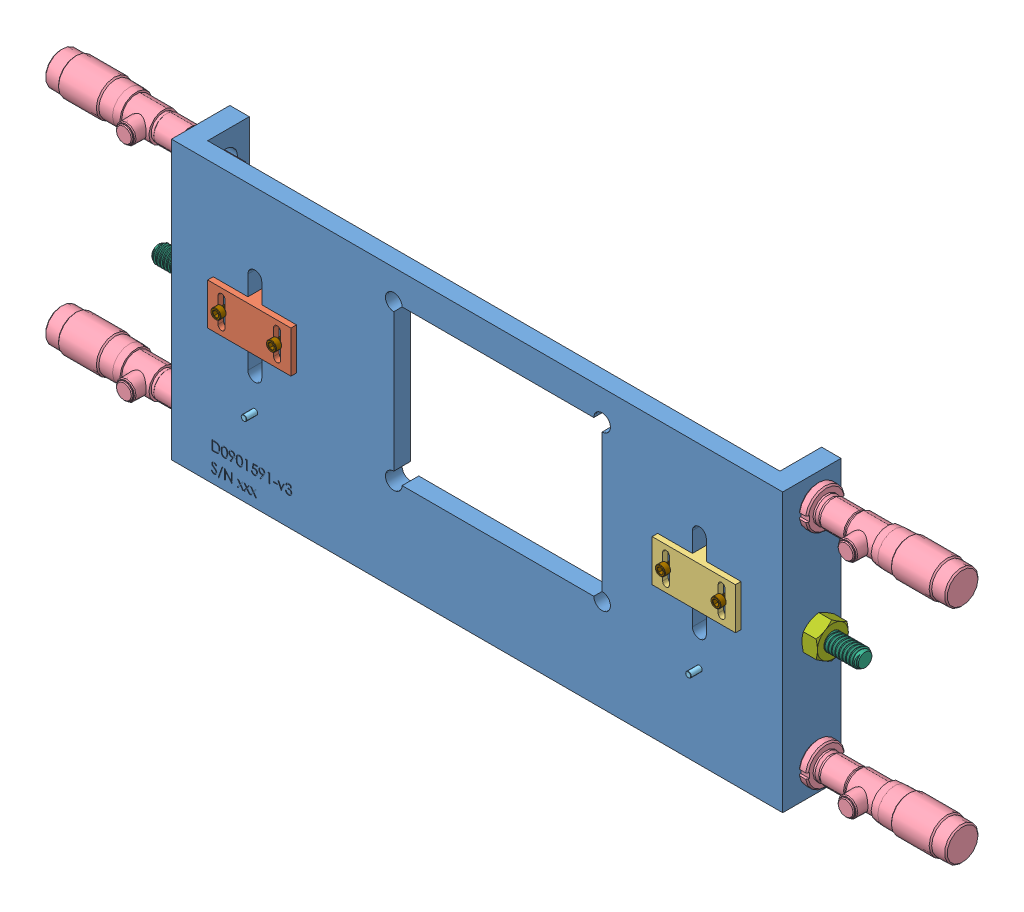
SolidWorks assembly Ear Bonding Jig Assembly, configuration Default. Lengths in mm.
Overall size (324.5 100 25.3).
20 component instances, 9 part files, 40 mates.
Components (placement in the parent):
- Baseplate-1: Baseplate [Default] at origin size (220 100 21)
- D1001633_T-piece-1: D1001633_T-piece [Default] at (0 -0.4 0) size (30 15 8)
- MVV_T_PIECE_1-1-1: MVV_T_PIECE_1-1 [Default] at (0 -0.4 0) size (30 15 8)
- Newport-HR-13-1: Newport-HR-13 [Default] at (-95.25 40 -6.5) x (0 1 0) z (0 0 1) size (14 67 16.68)
- Newport-HR-13-2: Newport-HR-13 [Default] at (-95.25 -40 -6.5) x (0 1 0) z (0 0 1) size (14 67 16.68)
- Newport-HR-13-3: Newport-HR-13 [Default] at (95.25 40 -6.5) x (0 -1 0) z (0 0 1) size (14 67 16.68)
- Newport-HR-13-4: Newport-HR-13 [Default] at (95.25 -40 -6.5) x (0 -1 0) z (0 0 1) size (14 67 16.68)
- Measurement Pin-1: Measurement Pin [Default] at (-80 -20 10) size (2 2 10)
- Measurement Pin-2: Measurement Pin [Default] at (80 -20 10) size (2 2 10)
- 8688A151-1: 8688A151 [8688A151] at (114.478 0 -6.5) x (0 1 0) z (0 0 1) size (6.35 30.18 6.6)
- 8688A151-2: 8688A151 [8688A151] at (-114.478 0 -6.5) x (0 -1 0) z (0 0 1) size (6.35 30.18 6.6)
- 94804A029-1: 94804A029 [94804A029] at (-110 0 -6.5) x (0 0 -1) z (1 0 0) size (11.11 12.83 6.47)
- 94804A029-2: 94804A029 [94804A029] at (110 0 -6.5) x (0 0 1) z (-1 0 0) size (11.11 12.83 6.47)
- bearing ball-1: bearing ball [Default] at (71.6135 -2.6969 2.7138) x (0.84085 0.476193 -0.257314) z (0.176522 0.208146 0.962037) size (6.35 6.35 6.35)
- bearing ball-2: bearing ball [Default] at (-70.0211 36.8174 2.425) size (6.35 6.35 6.35)
- bearing ball-3: bearing ball [Default] at (-69.9959 -43.171 2.425) size (6.35 6.35 6.35)
- 92185A078-1: 92185A078 [92185A078] at (-90 7.5 0.0625) x (-0.923728 -0.383049 0) z (0 0 -1) size (3.56 3.56 10.63)
- 92185A078-2: 92185A078 [92185A078] at (-70 7.5 0.0625) x (-0.923728 -0.383049 0) z (0 0 -1) size (3.56 3.56 10.63)
- 92185A078-3: 92185A078 [92185A078] at (70 7.5 0.0625) x (-0.923728 -0.383049 0) z (0 0 -1) size (3.56 3.56 10.63)
- 92185A078-4: 92185A078 [92185A078] at (90 7.5 0.0625) x (-0.923728 -0.383049 0) z (0 0 -1) size (3.56 3.56 10.63)
Mates (geometry in assembly coordinates):
- Coincident15: coincident aligned: plane of D1001633_T-piece-1 through (-95.6 -0.4 -0.16) normal (0 -1 0); plane of MVV_T_PIECE_1-1-1 through (64.4 -0.4 -0.16) normal (0 -1 0)
- Distance1: distance = 18.6 mm anti-aligned: plane of MVV_T_PIECE_1-1-1 through (64.4 -0.4 -0.16) normal (0 -1 0); plane of Baseplate-1 through (0 -19 0) normal (0 1 0)
- Coincident37: coincident anti-aligned: plane of Baseplate-1 through (77.5 22.31 -0.3311) normal (1 0 0); plane of MVV_T_PIECE_1-1-1 through (77.5 14.9 -0.12) normal (-1 0 0)
- Coincident38: coincident anti-aligned: plane of Baseplate-1 through (-114.6 -52 6) normal (0 0 1); plane of MVV_T_PIECE_1-1-1 through (95.25 14.9 6) normal (0 0 -1)
- Coincident39: coincident anti-aligned: plane of Baseplate-1 through (-82.5 22.31 -0.3311) normal (1 0 0); plane of D1001633_T-piece-1 through (-82.5 14.9 -0.12) normal (-1 0 0)
- Coincident40: coincident aligned: plane of D1001633_T-piece-1 through (-64.4 14.9 8) normal (0 0 1); plane of MVV_T_PIECE_1-1-1 through (95.6 14.9 8) normal (0 0 1)
- Parallel1: parallel aligned: plane of Newport-HR-13-1; plane of assembly through (0 0 0) normal (0 1 0)
- Parallel2: parallel aligned: plane of Newport-HR-13-2; plane of assembly through (0 0 0) normal (0 1 0)
- Parallel3: parallel anti-aligned: plane of Newport-HR-13-3; plane of assembly through (0 0 0) normal (0 1 0)
- Parallel4: parallel anti-aligned: plane of Newport-HR-13-4; plane of assembly through (0 0 0) normal (0 1 0)
- Concentric19: concentric anti-aligned: cylinder of Baseplate-1 through (-110 40 -6.5) axis (-1 0 0) radius 4.2164; cylinder of Newport-HR-13-1 through (-90.1409 40 -6.5) axis (1 0 0) radius 2.75
- Concentric20: concentric anti-aligned: cylinder of Baseplate-1 through (-110 -40 -6.5) axis (-1 0 0) radius 4.2164; cylinder of Newport-HR-13-2 through (-90.1409 -40 -6.5) axis (1 0 0) radius 2.75
- Concentric21: concentric anti-aligned: cylinder of Baseplate-1 through (110 40 -6.5) axis (1 0 0) radius 4.2164; cylinder of Newport-HR-13-3 through (90.1409 40 -6.5) axis (-1 0 0) radius 2.75
- Concentric22: concentric anti-aligned: cylinder of Baseplate-1 through (110 -40 -6.5) axis (1 0 0) radius 4.2164; cylinder of Newport-HR-13-4 through (90.1409 -40 -6.5) axis (-1 0 0) radius 2.75
- Coincident47: coincident anti-aligned: plane of Baseplate-1 through (-110 52 -10.3311) normal (-1 0 0); plane of Newport-HR-13-1 through (-110 35.2415 -6.5) normal (1 0 0)
- Coincident48: coincident anti-aligned: plane of Baseplate-1 through (-110 52 -10.3311) normal (-1 0 0); plane of Newport-HR-13-2 through (-110 -44.7585 -6.5) normal (1 0 0)
- Coincident49: coincident anti-aligned: plane of Newport-HR-13-3 through (110 44.7585 -6.5) normal (-1 0 0); plane of Baseplate-1 through (110 -50 -10) normal (1 0 0)
- Coincident50: coincident anti-aligned: plane of Newport-HR-13-4 through (110 -35.2415 -6.5) normal (-1 0 0); plane of Baseplate-1 through (110 -50 -10) normal (1 0 0)
- Concentric23: concentric aligned: cylinder of Baseplate-1 through (-80 -20 0) axis (0 0 1) radius 1; cylinder of Measurement Pin-1 through (-80 -20 0) axis (0 0 1) radius 1
- Coincident51: coincident aligned: plane of Baseplate-1 through (-104.6691 -52 0) normal (0 0 -1); plane of Measurement Pin-1 through (-80 -20 0) normal (0 0 -1)
- Coincident52: coincident aligned: plane of Baseplate-1 through (-104.6691 -52 0) normal (0 0 -1); plane of Measurement Pin-2 through (80 -20 0) normal (0 0 -1)
- Concentric24: concentric aligned: cylinder of Baseplate-1 through (80 -20 0) axis (0 0 1) radius 1; cylinder of Measurement Pin-2 through (80 -20 0) axis (0 0 1) radius 1
- Concentric32: concentric anti-aligned: cylinder of Baseplate-1 through (110 0 -6.5) axis (1 0 0) radius 2.5527; cylinder of 8688A151-1 through (97.0028 0 -6.5) axis (-1 0 0) radius 1.4986
- Distance2: distance = 3 mm anti-aligned: sphere of 8688A151-1; plane of Baseplate-1 through (103 50 0) normal (-1 0 0)
- Concentric33: concentric anti-aligned: cylinder of Baseplate-1 through (-110 0 -6.5) axis (-1 0 0) radius 2.5527; cylinder of 8688A151-2 through (-97.0028 0 -6.5) axis (1 0 0) radius 1.4986
- Distance3: distance = 3 mm anti-aligned: sphere of 8688A151-2; plane of Baseplate-1 through (-103 -50 0) normal (1 0 0)
- Coincident60: coincident anti-aligned: plane of Baseplate-1 through (-110 52 -10.3311) normal (-1 0 0); circle of 94804A029-1
- Concentric34: concentric anti-aligned: circle of 8688A151-2; circle of 94804A029-1
- Concentric35: concentric anti-aligned: circle of 8688A151-1; circle of 94804A029-2
- Distance4: distance = 0.75 mm aligned: plane of Baseplate-1 through (-104.6691 -52 0) normal (0 0 -1); sphere of bearing ball-1
- Distance7: distance = 0.75 mm aligned: plane of Baseplate-1 through (-104.6691 -52 0) normal (0 0 -1); sphere of bearing ball-2
- Distance9: distance = 0.75 mm aligned: plane of Baseplate-1 through (-104.6691 -52 0) normal (0 0 -1); sphere of bearing ball-3
- Coincident61: coincident anti-aligned: plane of 92185A078-1 through (-90 7.5 8) normal (0 0 -1); plane of D1001633_T-piece-1 through (-64.4 14.9 8) normal (0 0 1)
- Concentric36: concentric anti-aligned: circle of Baseplate-1; circle of 92185A078-1
- Coincident62: coincident anti-aligned: plane of 92185A078-2 through (-70 7.5 8) normal (0 0 -1); plane of D1001633_T-piece-1 through (-64.4 14.9 8) normal (0 0 1)
- Concentric37: concentric anti-aligned: circle of Baseplate-1; cylinder of 92185A078-2 through (-70 7.5 10.1844) axis (0 0 -1) radius 1.778
- Coincident63: coincident anti-aligned: plane of 92185A078-3 through (70 7.5 8) normal (0 0 -1); plane of MVV_T_PIECE_1-1-1 through (95.6 14.9 8) normal (0 0 1)
- Concentric38: concentric anti-aligned: circle of Baseplate-1; cylinder of 92185A078-3 through (70 7.5 10.1844) axis (0 0 -1) radius 1.778
- Coincident64: coincident anti-aligned: plane of 92185A078-4 through (90 7.5 8) normal (0 0 -1); plane of MVV_T_PIECE_1-1-1 through (95.6 14.9 8) normal (0 0 1)
- Concentric39: concentric anti-aligned: circle of Baseplate-1; cylinder of 92185A078-4 through (90 7.5 10.1844) axis (0 0 -1) radius 1.778
